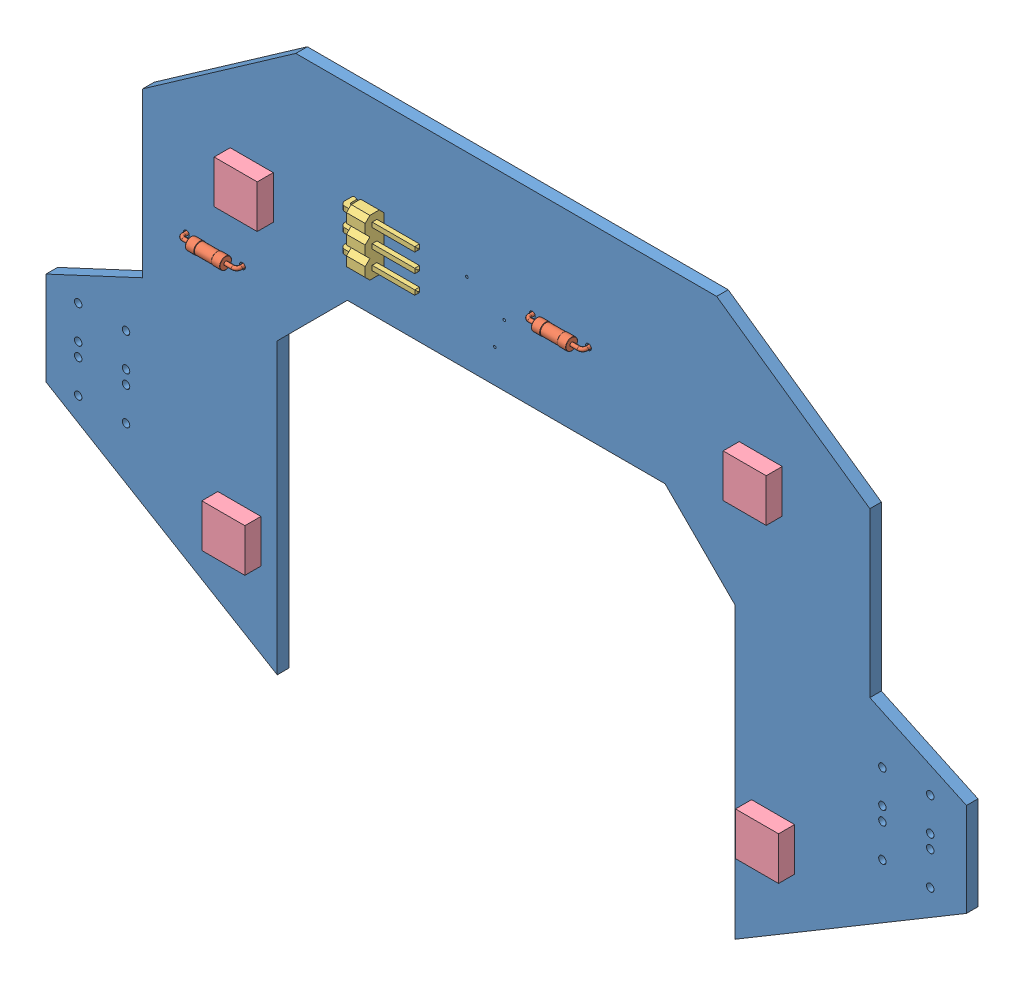
SolidWorks assembly backside_pcb_new_inv, configuration Default. Lengths in mm.
Overall size (125 74.35 5.54).
9 component instances, 4 part files, 0 mates.
Components (placement in the parent):
- PCB Component_1-1: PCB Component_1 [Default] at origin size (125 74.35 5.54)
  - Board_11-1: Board_11 [Default] at origin size (125 74.35 1.57)
  - 0204-7_R11-1: 0204-7_R11 [Default] at (69.85 59.69 1.57) x (-1 0 0) z (0 0 1) size (8.2 1.6 3.52)
  - 0204-7_R11-2: 0204-7_R11 [Default] at (22.86 45.72 1.57) size (8.2 1.6 3.52)
  - 1X03-90_JP2-1: 1X03-90_JP2 [Default] at (45.72 58.42 1.57) x (0 -1 0) z (0 0 1) size (7.62 10.36 5.54)
  - 3,6-PAD_H1-1: 3,6-PAD_H1 [Default] at (26.262 14.605 1.57) size (5.85 5.84 2.18)
  - 3,6-PAD_H1-2: 3,6-PAD_H1 [Default] at (27.94 55.88 1.57) size (5.85 5.84 2.18)
  - 3,6-PAD_H1-3: 3,6-PAD_H1 [Default] at (98.742 14.605 1.57) size (5.85 5.84 2.18)
  - 3,6-PAD_H1-4: 3,6-PAD_H1 [Default] at (97.064 55.88 1.57) size (5.85 5.84 2.18)
